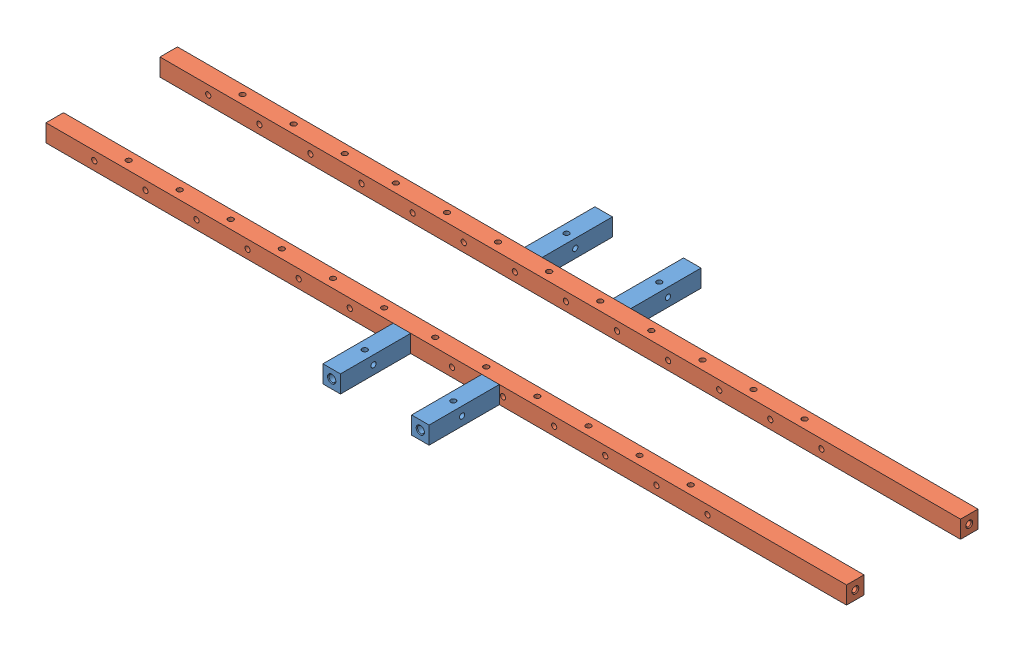
SolidWorks assembly frame_assembly, configuration Default. Lengths in mm.
Overall size (581 12.7 197.4).
6 component instances, 2 part files, 15 mates.
Components (placement in the parent):
- barstock support_short-1: barstock support_short [Default] at (-32.1571 6.85 -13.1239) x (0 0 -1) z (1 0 0) size (51 12.7 12.7)
- barstock support_short-2: barstock support_short [Default] at (32.1571 6.85 -64.1239) x (0 0 1) z (-1 0 0) size (51 12.7 12.7)
- barstock support_short-3: barstock support_short [Default] at (-32.1571 6.85 133.2761) x (0 0 -1) z (1 0 0) size (51 12.7 12.7)
- barstock support_short-4: barstock support_short [Default] at (32.1571 6.85 133.2761) x (0 0 -1) z (1 0 0) size (51 12.7 12.7)
- barstock support_long-1: barstock support_long [Default] at (-290.5 6.85 -6.7739) size (581 12.7 12.7)
- barstock support_long-2: barstock support_long [Default] at (-290.5 6.85 75.9261) size (581 12.7 12.7)
Mates (geometry in assembly coordinates):
- Coincident13: coincident aligned: plane of barstock support_long-1 through (320.65 0.5 -13.1239) normal (0 -1 0); plane of barstock support_short-1 through (-38.5071 0.5 -64.1239) normal (0 -1 0)
- Coincident14: coincident anti-aligned: plane of barstock support_long-1 through (320.65 0.5 -13.1239) normal (0 0 -1); plane of barstock support_short-1 through (-32.1571 6.85 -13.1239) normal (0 0 1)
- Coincident55: coincident aligned: plane of barstock support_short-1 through (-25.8071 0.5 -64.1239) normal (1 0 0); plane of barstock support_short-3 through (-25.8071 0.5 82.2761) normal (1 0 0)
- Coincident15: coincident anti-aligned: plane of barstock support_long-1 through (320.65 0.5 -13.1239) normal (0 0 -1); plane of barstock support_short-2 through (32.1571 6.85 -13.1239) normal (0 0 1)
- Coincident16: coincident aligned: plane of barstock support_long-1 through (320.65 13.2 -13.1239) normal (0 1 0); plane of barstock support_short-2 through (38.5071 13.2 -13.1239) normal (0 1 0)
- Coincident54: coincident aligned: plane of barstock support_short-2 through (25.8071 0.5 -13.1239) normal (-1 0 0); plane of barstock support_short-4 through (25.8071 0.5 82.2761) normal (-1 0 0)
- Coincident17: coincident anti-aligned: plane of barstock support_long-2 through (320.65 0.5 82.2761) normal (0 0 1); plane of barstock support_short-3 through (-32.1571 6.85 82.2761) normal (0 0 -1)
- Coincident18: coincident aligned: plane of barstock support_long-2 through (320.65 13.2 69.5761) normal (0 1 0); plane of barstock support_short-3 through (-38.5071 13.2 82.2761) normal (0 1 0)
- Coincident19: coincident anti-aligned: plane of barstock support_long-2 through (320.65 0.5 82.2761) normal (0 0 1); plane of barstock support_short-4 through (32.1571 6.85 82.2761) normal (0 0 -1)
- Coincident21: coincident aligned: plane of barstock support_long-2 through (320.65 13.2 69.5761) normal (0 1 0); plane of barstock support_short-4 through (25.8071 13.2 82.2761) normal (0 1 0)
- Distance1: distance = 70 mm anti-aligned: plane of barstock support_long-2 through (290.5 0.5 69.5761) normal (0 0 -1); plane of barstock support_long-1 through (290.5 0.5 -0.4239) normal (0 0 1)
- Coincident84: coincident aligned: plane of barstock support_long-1 through (320.65 13.2 -13.1239) normal (0 1 0); plane of barstock support_long-2 through (320.65 13.2 69.5761) normal (0 1 0)
- Coincident86: coincident aligned: plane of barstock support_long-1 through (320.65 6.85 -6.7739) normal (1 0 0); plane of barstock support_long-2 through (320.65 6.85 75.9261) normal (1 0 0)
- Symmetric1: symmetric aligned: plane of barstock support_short-1 through (-25.8071 0.5 -64.1239) normal (1 0 0); plane of barstock support_short-2 through (25.8071 0.5 -13.1239) normal (-1 0 0)
- Symmetric2: symmetric aligned: plane of barstock support_long-1 through (-290.5 6.85 -6.7739) normal (-1 0 0); plane of barstock support_long-1 through (290.5 6.85 -6.7739) normal (1 0 0)
